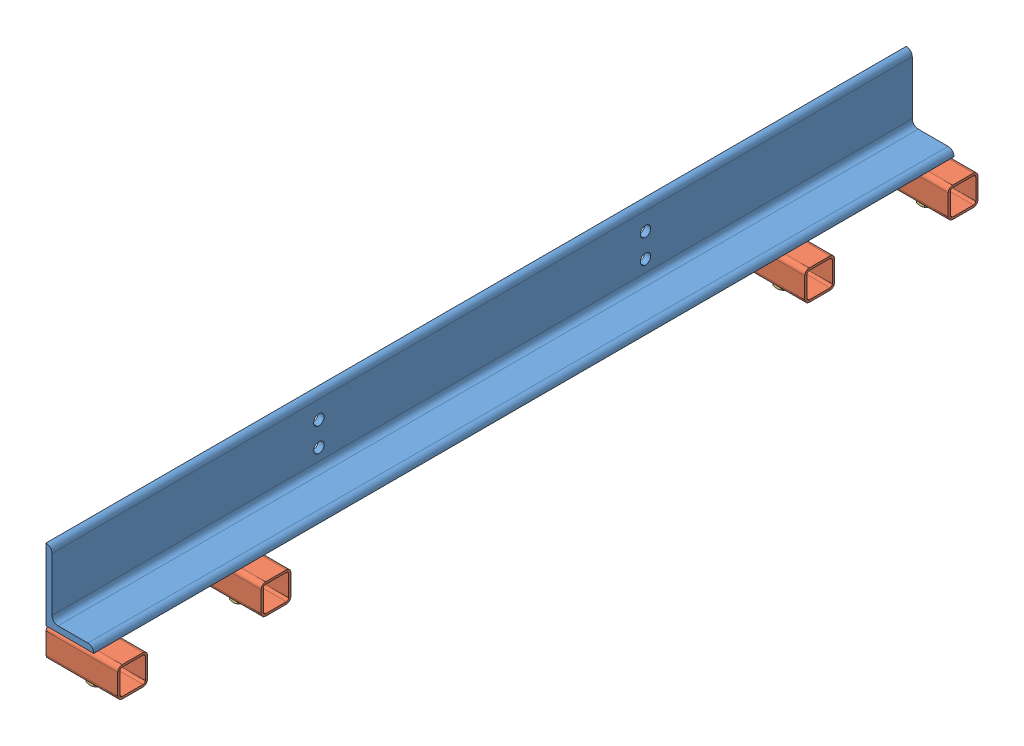
SolidWorks assembly 01-003-00-0, configuration Default. Lengths in mm.
Overall size (152.4 232.79 1828.8).
13 component instances, 3 part files, 12 mates.
Components (placement in the parent):
- 01-004-00-0-3: 01-004-00-0 [Default] at (-6.35 0 0) size (101.6 152.4 1828.8)
- Leg Support Ass-1: Leg Support Ass [Default] at (85.8425 -28.4478 -917.2083) x (0 0 -1) z (-1 0 0) size (63.5 80.39 152.4)
  - leg_2-1: leg_2 [TS2.5x2.5x0.1875x6] at (-66.3083 -28.4478 15.9925) size (63.5 63.5 152.4)
  - hex nut_ai-1: hex nut_ai [HNUT 0.7500-10-D-C] at (-34.5474 51.9432 15.9925) x (1 0 0) z (0 1 0) size (28.57 33 16.89)
- Leg Support Ass-2: Leg Support Ass [Default] at (85.8425 -28.4478 -612.4083) x (0 0 -1) z (-1 0 0) size (63.5 80.39 152.4)
  - leg_2-1: leg_2 [TS2.5x2.5x0.1875x6] at (-66.3083 -28.4478 15.9925) size (63.5 63.5 152.4)
  - hex nut_ai-1: hex nut_ai [HNUT 0.7500-10-D-C] at (-34.5474 51.9432 15.9925) x (1 0 0) z (0 1 0) size (28.57 33 16.89)
- Leg Support Ass-3: Leg Support Ass [Default] at (85.8425 -28.4478 543.2917) x (0 0 -1) z (-1 0 0) size (63.5 80.39 152.4)
  - leg_2-1: leg_2 [TS2.5x2.5x0.1875x6] at (-66.3083 -28.4478 15.9925) size (63.5 63.5 152.4)
  - hex nut_ai-1: hex nut_ai [HNUT 0.7500-10-D-C] at (-34.5474 51.9432 15.9925) x (1 0 0) z (0 1 0) size (28.57 33 16.89)
- Leg Support Ass-4: Leg Support Ass [Default] at (85.8425 -28.4478 848.0917) x (0 0 -1) z (-1 0 0) size (63.5 80.39 152.4)
  - leg_2-1: leg_2 [TS2.5x2.5x0.1875x6] at (-66.3083 -28.4478 15.9925) size (63.5 63.5 152.4)
  - hex nut_ai-1: hex nut_ai [HNUT 0.7500-10-D-C] at (-34.5474 51.9432 15.9925) x (1 0 0) z (0 1 0) size (28.57 33 16.89)
Mates (geometry in assembly coordinates):
- Coincident1: coincident anti-aligned: plane of 01-004-00-0-3 through (95.25 0 914.4) normal (0 -1 0); plane of Leg Support Ass-1/leg_2-1 through (-6.35 0 -860.425) normal (0 1 0)
- Coincident2: coincident anti-aligned: plane of 01-004-00-0-3 through (95.25 0 914.4) normal (0 -1 0); plane of Leg Support Ass-2/leg_2-1 through (-6.35 0 -555.625) normal (0 1 0)
- Coincident3: coincident anti-aligned: plane of 01-004-00-0-3 through (95.25 0 914.4) normal (0 -1 0); plane of Leg Support Ass-3/leg_2-1 through (-6.35 0 600.075) normal (0 1 0)
- Coincident4: coincident anti-aligned: plane of 01-004-00-0-3 through (95.25 0 914.4) normal (0 -1 0); plane of Leg Support Ass-4/leg_2-1 through (-6.35 0 904.875) normal (0 1 0)
- Coincident5: coincident aligned: plane of 01-004-00-0-3 through (-6.35 0 914.4) normal (-1 0 0); plane of Leg Support Ass-1/leg_2-1 through (-6.35 -53.975 -904.875) normal (-1 0 0)
- Coincident6: coincident aligned: plane of 01-004-00-0-3 through (-6.35 0 914.4) normal (-1 0 0); plane of Leg Support Ass-2/leg_2-1 through (-6.35 -53.975 -600.075) normal (-1 0 0)
- Coincident7: coincident aligned: plane of 01-004-00-0-3 through (-6.35 0 914.4) normal (-1 0 0); plane of Leg Support Ass-3/leg_2-1 through (-6.35 -53.975 555.625) normal (-1 0 0)
- Coincident8: coincident aligned: plane of 01-004-00-0-3 through (-6.35 0 914.4) normal (-1 0 0); plane of Leg Support Ass-4/leg_2-1 through (-6.35 -53.975 860.425) normal (-1 0 0)
- Coincident9: coincident aligned: plane of 01-004-00-0-3 through (-6.3449 139.7051 914.4) normal (0 0 1); plane of Leg Support Ass-4/leg_2-1 through (-6.35 -9.525 914.4) normal (0 0 1)
- Distance1: distance = 304.8 mm aligned: plane of Leg Support Ass-3/leg_2-1 through (-6.35 -9.525 609.6) normal (0 0 1); plane of Leg Support Ass-4/leg_2-1 through (-6.35 -9.525 914.4) normal (0 0 1)
- Coincident11: coincident aligned: plane of 01-004-00-0-3 through (-6.3449 139.7051 -914.4) normal (0 0 -1); plane of Leg Support Ass-1/leg_2-1 through (-6.35 -53.975 -914.4) normal (0 0 -1)
- Distance2: distance = 304.8 mm aligned: plane of Leg Support Ass-1/leg_2-1 through (-6.35 -53.975 -914.4) normal (0 0 -1); plane of Leg Support Ass-2/leg_2-1 through (-6.35 -53.975 -609.6) normal (0 0 -1)
